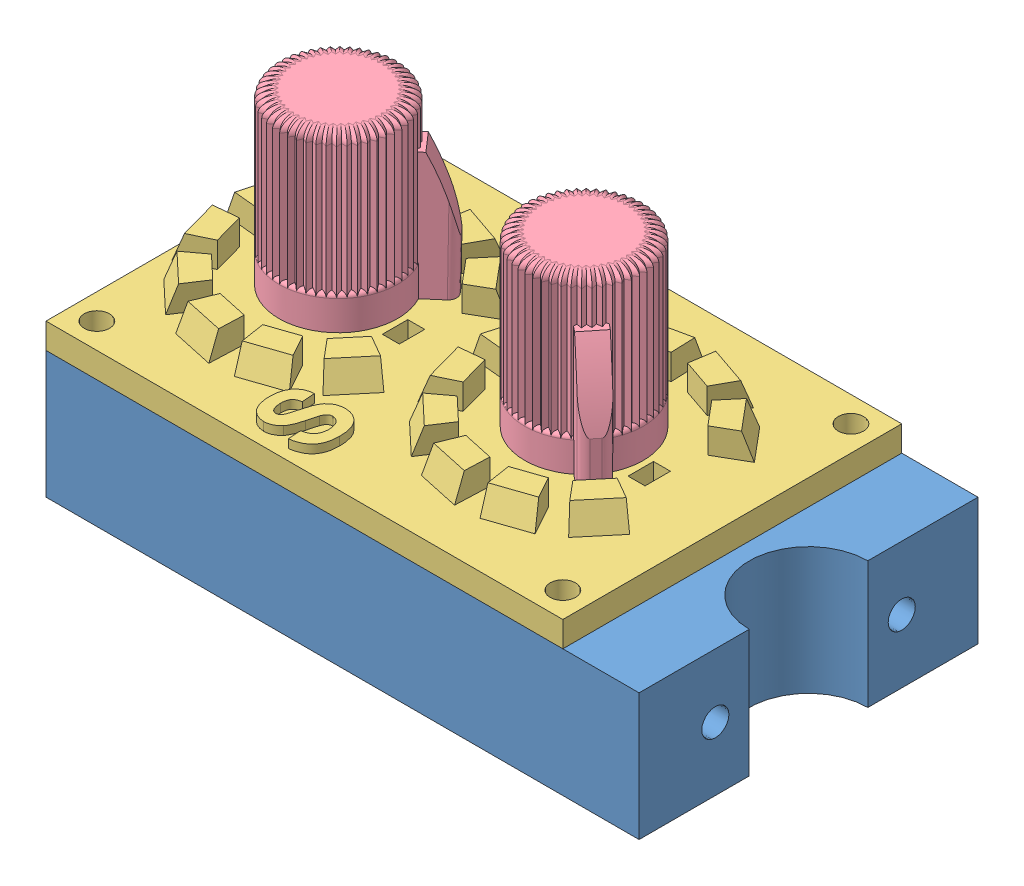
SolidWorks assembly sens_control_panel, configuration По умолчанию. Lengths in mm.
Overall size (70 39 40).
6 component instances, 4 part files, 12 mates.
Components (placement in the parent):
- scpnl_box_scpnl01-1: scpnl_box_scpnl01 [По умолчанию] at origin size (70 15 40)
- 16K1-B10K-1: 16K1-B10K [По умолчанию] at (-20.5 6.1 0) x (0.05666 0 -0.998394) z (0.998394 0 0.05666) size (20 28.16 16.3)
- scpnl_box_lid_scpnl02-1: scpnl_box_lid_scpnl02 [По умолчанию] at (0 15 0) size (61 6 40)
- 16K1-B10K-2: 16K1-B10K [По умолчанию] at (8.5 6.1 0) x (0 0 -1) z (1 0 0) size (20 28.16 16.3)
- scpnl_sens_knob_scpnl03-1: scpnl_sens_knob_scpnl03 [По умолчанию] at (-20.5 19 0) x (0.754759 0 -0.656002) z (0.656002 0 0.754759) size (17.76 20 14.06)
- scpnl_sens_knob_scpnl03-2: scpnl_sens_knob_scpnl03 [По умолчанию] at (8.5 19 0) x (0.780165 0 0.625574) z (-0.625574 0 0.780165) size (17.76 20 14.06)
Mates (geometry in assembly coordinates):
- Concentric1: concentric aligned: cylinder of scpnl_box_scpnl01-1 through (23 0 -17) axis (0 1 0) radius 1.45; cylinder of scpnl_box_lid_scpnl02-1 through (23 15 -17) axis (0 1 0) radius 1.5
- Coincident1: coincident anti-aligned: plane of scpnl_box_scpnl01-1 through (35 15 0) normal (0 1 0); plane of scpnl_box_lid_scpnl02-1 through (35 15 0) normal (0 -1 0)
- Concentric2: concentric aligned: cylinder of scpnl_box_scpnl01-1 through (-32 0 17) axis (0 1 0) radius 1.45; cylinder of scpnl_box_lid_scpnl02-1 through (-32 15 17) axis (0 1 0) radius 1.5
- Concentric3: concentric anti-aligned: cylinder of 16K1-B10K-1 through (-20.5 21.4 0) axis (0 -1 0) radius 3.35; cylinder of scpnl_box_lid_scpnl02-1 through (-20.5 15 0) axis (0 1 0) radius 3.7
- Concentric4: concentric anti-aligned: cylinder of scpnl_box_lid_scpnl02-1 through (8.5 15 0) axis (0 1 0) radius 3.7; cylinder of 16K1-B10K-2 through (8.5 21.4 0) axis (0 -1 0) radius 3.35
- Coincident2: coincident anti-aligned: plane of 16K1-B10K-1 through (-20.5 15 0) normal (0 1 0); plane of scpnl_box_lid_scpnl02-1 through (35 15 0) normal (0 -1 0)
- Coincident3: coincident anti-aligned: plane of scpnl_box_lid_scpnl02-1 through (35 15 0) normal (0 -1 0); plane of 16K1-B10K-2 through (8.5 15 0) normal (0 1 0)
- Parallel1: parallel aligned: plane of scpnl_box_lid_scpnl02-1 through (26 -49.6607 17) normal (1 0 0); plane of 16K1-B10K-2 through (16.65 13.2 0) normal (1 0 0)
- Concentric5: concentric aligned: cylinder of 16K1-B10K-1 through (-20.5 34.2 0) axis (0 -1 0) radius 2.9; cylinder of scpnl_sens_knob_scpnl03-1 through (-20.5 36 0) axis (0 -1 0) radius 3.125
- Distance2: distance = 1 mm anti-aligned: plane of scpnl_sens_knob_scpnl03-1 through (-20.5 19 0) normal (0 -1 0); plane of scpnl_box_lid_scpnl02-1 through (35 18 0) normal (0 1 0)
- Concentric6: concentric aligned: cylinder of 16K1-B10K-2 through (8.5 34.2 0) axis (0 -1 0) radius 2.9; cylinder of scpnl_sens_knob_scpnl03-2 through (8.5 36 0) axis (0 -1 0) radius 3.125
- Distance3: distance = 1 mm anti-aligned: plane of scpnl_sens_knob_scpnl03-2 through (8.5 19 0) normal (0 -1 0); plane of scpnl_box_lid_scpnl02-1 through (35 18 0) normal (0 1 0)
